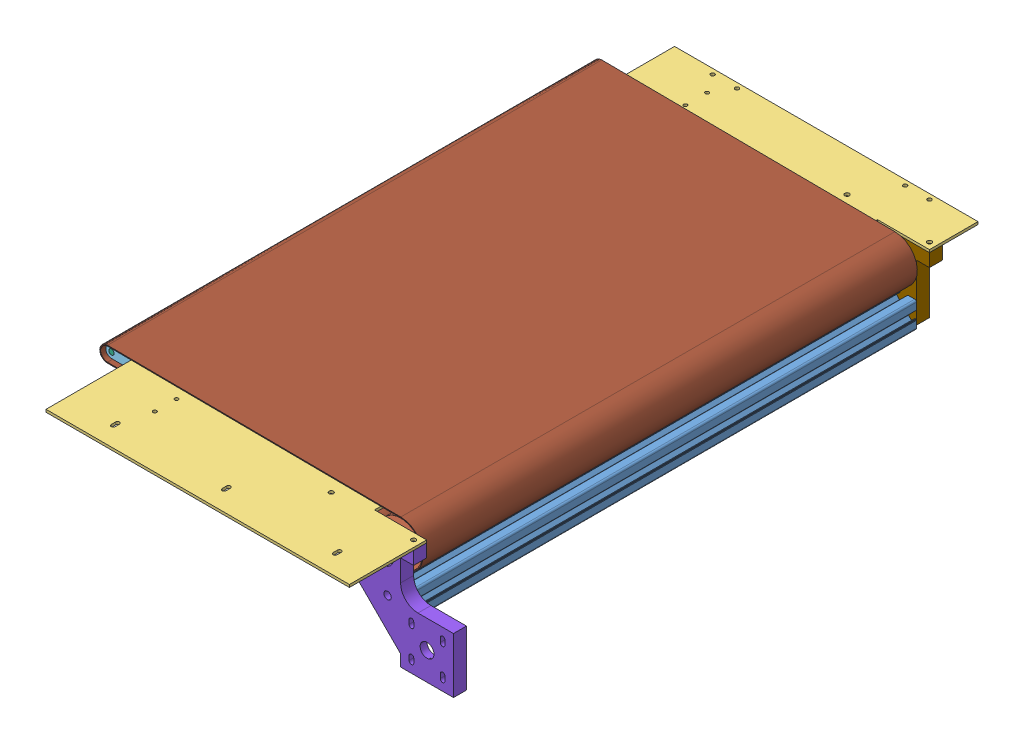
SolidWorks assembly 下床板装配体, configuration 默认. Lengths in mm.
Overall size (428.36 136.72 725).
29 component instances, 14 part files, 27 mates.
Components (placement in the parent):
- 3030_382mm_下床板梁-1: 3030_382mm_下床板梁 [默认] at (-5.2917 1.5503 291) size (30 30 580)
- 传送带筒_下床板mm-1: 传送带筒_下床板mm [默认] at (-10.2917 51.5503 840.4406) x (0 0 -1) z (-0.386411 0.922327 0) size (644.48 50 50)
- 下床板-2: 下床板 [默认] at (6.182 77.7858 235) x (-1 0 0) z (0 0 1) size (350 3 725)
- 从动滚筒装配体-1: 从动滚筒装配体 [默认] at (-357.512 68.669 943) x (-1 0 0) z (0 0 -1) size (60.88 17.76 280)
  - 从动滚筒滚筒_亚克力-1: 从动滚筒滚筒_亚克力 [默认] at (-9.2203 2.3813 103) size (16 16 237)
  - 从动滚筒架-1: 从动滚筒架 [默认] at (-32.9493 -0.0698 342.5) size (58.5 13 19)
  - 从动滚筒轴-1: 从动滚筒轴 [默认] at (-9.2203 2.3813 334.1374) x (0 0 -1) z (1 0 0) size (280 10 10)
  - 从动滚筒架-2: 从动滚筒架 [默认] at (-32.9493 -0.0698 81.5) size (58.5 13 19)
  - SFL678ZZ深沟球法兰杯轴承-1: SFL678ZZ深沟球法兰杯轴承 [默认] at (-9.2203 2.3813 104.4) x (0 0 -1) z (1 0 0) size (4.3 13.6 13.6)
  - SFL678ZZ深沟球法兰杯轴承-2: SFL678ZZ深沟球法兰杯轴承 [默认] at (-9.2203 2.3813 338.6) x (0 0 1) z (0.381849 0.924225 0) size (4.3 13.6 13.6)
- 从动滚筒装配体-2: 从动滚筒装配体 [默认] at (-357.512 68.669 662) x (-1 0 0) z (0 0 -1) size (60.88 17.76 280)
  - 从动滚筒滚筒_亚克力-1: 从动滚筒滚筒_亚克力 [默认] at (-9.2203 2.3813 103) size (16 16 237)
  - 从动滚筒架-1: 从动滚筒架 [默认] at (-32.9493 -0.0698 342.5) size (58.5 13 19)
  - 从动滚筒轴-1: 从动滚筒轴 [默认] at (-9.2203 2.3813 334.1374) x (0 0 -1) z (1 0 0) size (280 10 10)
  - 从动滚筒架-2: 从动滚筒架 [默认] at (-32.9493 -0.0698 81.5) size (58.5 13 19)
  - SFL678ZZ深沟球法兰杯轴承-1: SFL678ZZ深沟球法兰杯轴承 [默认] at (-9.2203 2.3813 104.4) x (0 0 -1) z (1 0 0) size (4.3 13.6 13.6)
  - SFL678ZZ深沟球法兰杯轴承-2: SFL678ZZ深沟球法兰杯轴承 [默认] at (-9.2203 2.3813 338.6) x (0 0 1) z (0.381849 0.924225 0) size (4.3 13.6 13.6)
- 床板架_带电机架-1: 床板架_带电机架 [默认] at (-51.4907 30.1211 871) size (156 124 15)
- 下床板架 - 镜像-1: 下床板架 - 镜像 [默认] at (-51.4907 30.1668 276) size (110 80 15)
- radial ball bearing_68_skf-1: radial ball bearing_68_skf [SKF - 61803 - 20,SI,NC,20_68] at (-10.2917 51.5503 283.5) x (0 0 -1) z (1 0 0) size (5 26 26)
- radial ball bearing_68_skf-2: radial ball bearing_68_skf [SKF - 61803 - 20,SI,NC,20_68] at (-10.2917 51.5503 878.5) x (0 0 1) z (-1 0 0) size (5 26 26)
- 传送带_下床板-1: 传送带_下床板 [默认] at (-335.866 78.9586 296) x (0.999973 -0.007395 0) z (0 0 1) size (373.17 52 570)
- 下床板支撑机构-1: 下床板支撑机构 [默认] at (-302.7917 62.4213 266.2971) x (0 0 -1) z (1 0.000002 0) size (645 23.37 29.37)
  - 床板支撑架-1: 床板支撑架 [默认] at (-8.7029 4.1289 28) size (33 20 28)
  - 床板支撑架-2: 床板支撑架 [默认] at (-620.7029 4.1289 28) x (1 0 0) z (0 -0.000002 1) size (33 20 28)
  - 铬光棒_645mm-1: 铬光棒_645mm [默认] at (7.7971 -3.8711 28) x (0 0 1) z (-1 0 0) size (8 8 645)
  - 亚克力_575mm-1: 亚克力_575mm [默认] at (-602.2029 -3.8711 28) x (0 0.365618 -0.930765) z (1 0 0) size (16 16 575)
  - SFL678ZZ深沟球法兰杯轴承-1: SFL678ZZ深沟球法兰杯轴承 [默认] at (-28.6029 -3.8711 28) size (4.3 13.6 13.6)
  - SFL678ZZ深沟球法兰杯轴承-2: SFL678ZZ深沟球法兰杯轴承 [默认] at (-600.8029 -3.8711 28) x (-1 0 0) z (0 -0.924225 -0.381849) size (4.3 13.6 13.6)
Mates (geometry in assembly coordinates):
- 重合12: coincident: plane of 下床板-2 through (24.7083 71.5503 960) normal (0 -1 0); plane of 从动滚筒装配体-2/从动滚筒架-1 through (-296.2917 71.5503 300.5) normal (0 1 0)
- 同心14: concentric: cylinder of 下床板-2 through (-304.2917 81.5503 566) axis (0 -1 0) radius 2.25; cylinder of 从动滚筒装配体-2/从动滚筒架-2 through (-304.2917 51.5503 566) axis (0 1 0) radius 2.25
- 重合14: coincident: plane of 下床板-2 through (24.7083 71.5503 960) normal (0 -1 0); plane of 从动滚筒装配体-1/从动滚筒架-1 through (-296.2917 71.5503 581.5) normal (0 1 0)
- 同心21: concentric: cylinder of 下床板-2 through (-304.2917 81.5503 857) axis (0 -1 0) radius 2.25; cylinder of 从动滚筒装配体-1/从动滚筒架-2 through (-304.2917 51.5503 857) axis (0 1 0) radius 2.25
- 同心22: concentric: cylinder of 下床板-2 through (-304.2917 81.5503 586) axis (0 -1 0) radius 2.25; cylinder of 从动滚筒装配体-1/从动滚筒架-1 through (-304.2917 51.5503 586) axis (0 1 0) radius 2.25
- 同心23: concentric: cylinder of 下床板-2 through (-304.2917 81.5503 305) axis (0 -1 0) radius 2.25; cylinder of 从动滚筒装配体-2/从动滚筒架-1 through (-304.2917 51.5503 305) axis (0 1 0) radius 2.25
- 重合16: coincident: plane of 下床板-2 through (24.7083 71.5503 960) normal (0 -1 0); plane of 床板架_带电机架-1 through (-85.2917 71.5503 886) normal (0 1 0)
- 同心27: concentric: cylinder of 下床板-2 through (17.2083 81.5503 878.5) axis (0 -1 0) radius 2.6; cylinder of 床板架_带电机架-1 through (17.2083 -52.4507 878.5) axis (0 1 0) radius 2.6
- 同心28: concentric: cylinder of 下床板-2 through (-77.7917 81.5503 878.5) axis (0 -1 0) radius 2.6; cylinder of 床板架_带电机架-1 through (-77.7917 -52.4507 878.5) axis (0 1 0) radius 2.6
- 平行2: parallel: cylinder of 下床板架 - 镜像-1 through (17.2083 -8.4497 283.5) axis (0 1 0) radius 2.6; cylinder of 下床板-2 through (17.2083 81.5503 283.5) axis (0 -1 0) radius 2.6
- 同心35: concentric: cylinder of 下床板-2 through (-77.7917 81.5503 283.5) axis (0 -1 0) radius 2.6; cylinder of 下床板架 - 镜像-1 through (-77.7917 -8.4497 283.5) axis (0 1 0) radius 2.6
- 同心36: concentric: cylinder of 3030_382mm_下床板梁-1 through (-5.2917 1.5503 291) axis (0 0 1) radius 3.4; cylinder of 下床板架 - 镜像-1 through (-5.2917 1.5503 291) axis (0 0 -1) radius 4.25
- 重合21: coincident: plane of 3030_382mm_下床板梁-1 through (-5.2917 1.5503 291) normal (0 0 -1); plane of 下床板架 - 镜像-1 through (-51.4907 30.1668 291) normal (0 0 1)
- 平行3: parallel: plane of 3030_382mm_下床板梁-1 through (-10.3917 -13.4497 871) normal (0 -1 0); plane of 下床板架 - 镜像-1 through (-21.0024 -8.4497 291) normal (0 -1 0)
- 同心37: concentric: cylinder of 传送带筒_下床板mm-1 through (-10.2917 51.5503 903.1465) axis (0 0 1) radius 8.5; cylinder of radial ball bearing_68_skf-1 through (-10.2917 51.5503 304.1375) axis (0 0 -1) radius 8.5
- 重合22: coincident: plane of 传送带筒_下床板mm-1 through (-19.515 47.6862 286) normal (0 0 -1); plane of radial ball bearing_68_skf-1 through (-10.2917 61.4003 286) normal (0 0 1)
- 重合23: coincident: plane of 下床板架 - 镜像-1 through (-10.2917 51.5503 281) normal (0 0 1); plane of radial ball bearing_68_skf-1 through (-10.2917 64.2503 281) normal (0 0 -1)
- 同心38: concentric: cylinder of 下床板架 - 镜像-1 through (-10.2917 51.5503 281) axis (0 0 1) radius 13.05; cylinder of radial ball bearing_68_skf-1 through (-10.2917 51.5503 304.1375) axis (0 0 -1) radius 8.5
- 同心39: concentric: cylinder of 床板架_带电机架-1 through (-10.2917 51.5503 881) axis (0 0 -1) radius 13.1; cylinder of radial ball bearing_68_skf-2 through (-10.2917 51.5503 857.8625) axis (0 0 1) radius 13
- 重合24: coincident: plane of 床板架_带电机架-1 through (-10.2917 51.5503 881) normal (0 0 -1); plane of radial ball bearing_68_skf-2 through (-10.2917 64.2503 881) normal (0 0 1)
- 同心40: concentric: cylinder of 传送带筒_下床板mm-1 through (-10.2917 51.5503 903.1465) axis (0 0 1) radius 8.5; cylinder of radial ball bearing_68_skf-2 through (-10.2917 51.5503 857.8625) axis (0 0 1) radius 8.5
- 同心41: concentric: cylinder of 传送带筒_下床板mm-1 through (-10.2917 51.5503 903.1465) axis (0 0 1) radius 25; cylinder of 传送带_下床板-1 through (-10.2917 51.5503 866) axis (0 0 -1) radius 25
- 平行6: parallel: plane of 传送带_下床板-1 through (-348.2706 79.0504 866) normal (-0.007395 -0.999973 0); plane of assembly through (0.5655 76.4707 0) normal (0.007395 0.999973 0)
- 重合27: coincident: plane of 传送带筒_下床板mm-1 through (-33.3499 41.89 866) normal (0 0 1); plane of 传送带_下床板-1 through (-50.9889 44.5575 866) normal (0 0 1)
- 同心42: concentric: cylinder of 下床板-2 through (-260.2917 81.5503 899.5) axis (0 -1 0) radius 2.05; cylinder of 下床板支撑机构-1/床板支撑架-2 through (-260.2917 103.5503 899.5) axis (0 -1 0) radius 2.25
- 同心43: concentric: cylinder of 下床板-2 through (-260.2917 81.5503 874.5) axis (0 -1 0) radius 2.05; cylinder of 下床板支撑机构-1/床板支撑架-2 through (-260.2917 103.5503 874.5) axis (0 -1 0) radius 2.25
- 重合28: coincident: plane of 下床板-2 through (24.7083 71.5503 960) normal (0 -1 0); plane of 下床板支撑机构-1/床板支撑架-2 through (-274.7917 71.5503 887) normal (0 1 0)
